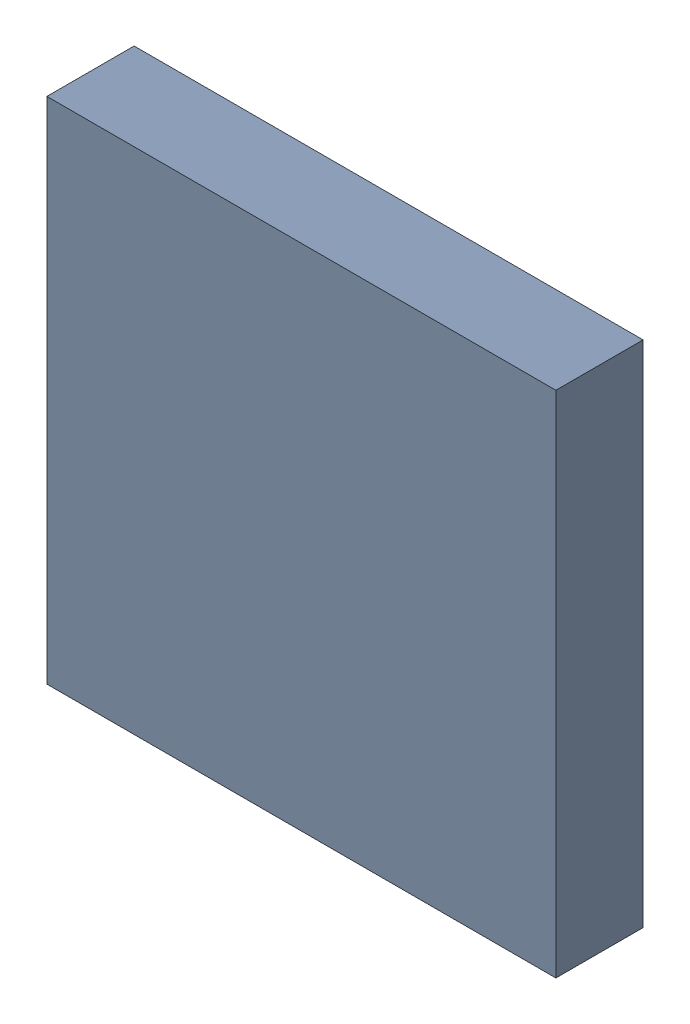
SolidWorks assembly U4, configuration Default. Lengths in mm.
Overall size (7 7 1.2).
2 component instances, 1 part files, 0 mates.
Components (placement in the parent):
- 959209752-1: 959209752 [Default] at (110.9632 83.702 0) size (7 7 1.2)
  - Extruded-28-1: Extruded-28 [Default] at origin size (7 7 1.2)
